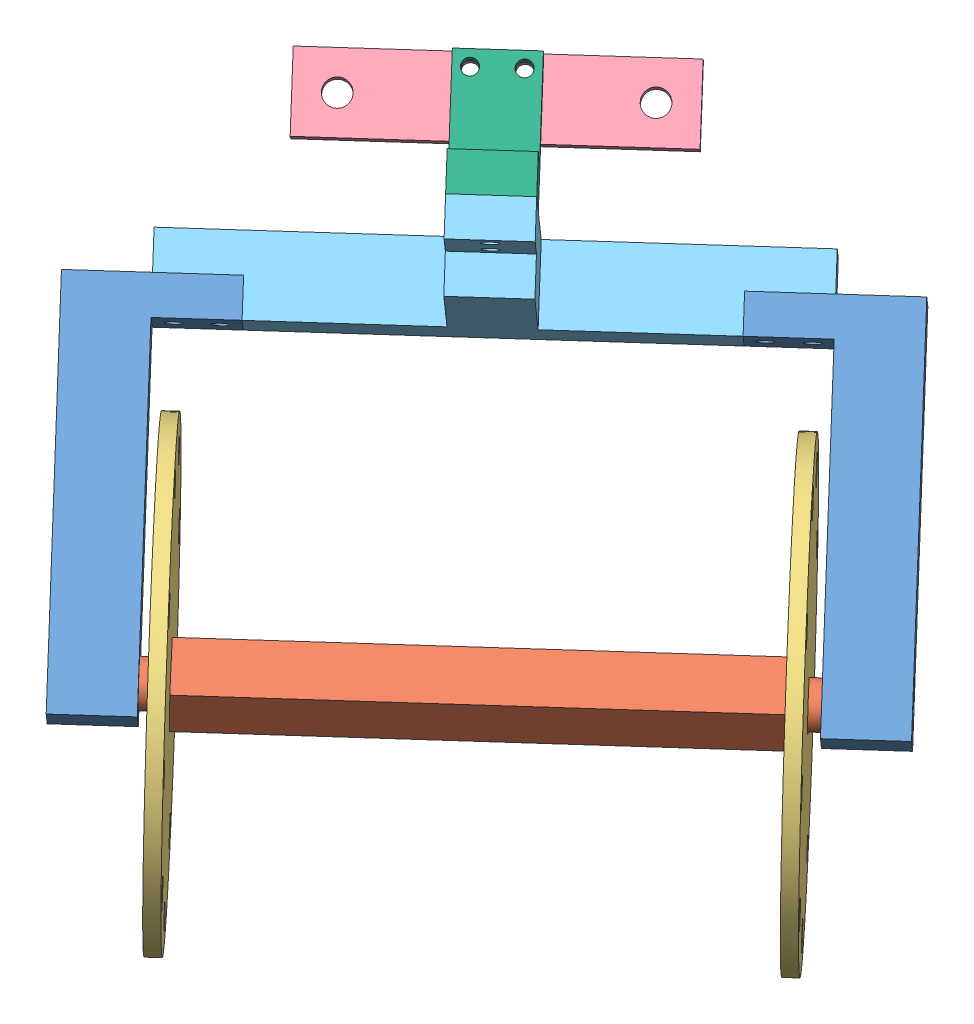
SolidWorks assembly assembly_20241201, configuration 默认. Lengths in mm.
Overall size (218.69 227.91 217.94).
8 component instances, 6 part files, 19 mates.
Components (placement in the parent):
- connecter_ear_3D_printing_20241201-3: connecter_ear_3D_printing_20241201 [默认] at (273.7366 -111.631 197.0743) x (-0.457434 0.731579 -0.505516) z (0.507347 0.681586 0.527294) size (98.5 40 16)
- connecter_ear_3D_printing_20241201-4: connecter_ear_3D_printing_20241201 [默认] at (383.2831 -113.9215 94.6325) x (-0.457434 0.731579 -0.505516) z (-0.507347 -0.681586 -0.527294) size (98.5 40 16)
- core_stick_3D_printing_20241201-3: core_stick_3D_printing_20241201 [默认] at (378.1709 -113.8146 99.4132) x (0.272303 0.923395 0.270542) z (0.626497 -0.383547 0.678523) size (15 176 15)
- sidewall_acrylic_4mm_20241201-5: sidewall_acrylic_4mm_20241201 [默认] at (378.1709 -113.8146 99.4132) x (0.65086 -0.288029 0.702439) z (0.207434 0.9575 0.200412) size (120 4 120)
- sidewall_acrylic_4mm_20241201-6: sidewall_acrylic_4mm_20241201 [默认] at (275.9275 -111.6768 195.0255) x (0.65086 -0.288029 0.702439) z (0.207434 0.9575 0.200412) size (120 4 120)
- connecter_tail_acrylic_4mm_20241202-1: connecter_tail_acrylic_4mm_20241202 [默认] at (296.1906 12.0688 108.5013) x (0.73031 -0.01527 -0.682945) z (0.457434 -0.731579 0.505516) size (90 4 20)
- connecter_body_3D_printing_20241201-5: connecter_body_3D_printing_20241201 [默认] at (282.7664 -39.6184 95.3018) x (-0.73031 0.01527 0.682945) z (0.507347 0.681586 0.527294) size (150 20 86)
- connecter_fixer_3D_printing-1: connecter_fixer_3D_printing [默认] at (317.266 6.7295 131.1578) x (0.73031 -0.01527 -0.682945) z (-0.457434 0.731579 -0.505516) size (20 25 35)
Mates (geometry in assembly coordinates):
- 同心6: concentric anti-aligned: cylinder of connecter_ear_3D_printing_20241201-3 through (259.1304 -111.3256 210.7332) axis (0.73031 -0.01527 -0.682945) radius 6.5; cylinder of core_stick_3D_printing_20241201-3 through (392.7771 -114.12 85.7543) axis (-0.73031 0.01527 0.682945) radius 6
- 同心7: concentric aligned: cylinder of core_stick_3D_printing_20241201-3 through (392.7771 -114.12 85.7543) axis (-0.73031 0.01527 0.682945) radius 6; cylinder of sidewall_acrylic_4mm_20241201-5 through (381.0922 -113.8757 96.6814) axis (-0.73031 0.01527 0.682945) radius 6.6
- 同心9: concentric anti-aligned: cylinder of core_stick_3D_printing_20241201-3 through (264.2426 -111.4325 205.9526) axis (0.73031 -0.01527 -0.682945) radius 6; cylinder of sidewall_acrylic_4mm_20241201-6 through (278.8488 -111.7379 192.2937) axis (-0.73031 0.01527 0.682945) radius 6.6
- 重合6: coincident anti-aligned: plane of core_stick_3D_printing_20241201-3 through (278.8488 -111.7379 192.2937) normal (-0.73031 0.01527 0.682945); plane of sidewall_acrylic_4mm_20241201-6 through (278.8488 -111.7379 192.2937) normal (0.73031 -0.01527 -0.682945)
- 同心17: concentric aligned: cylinder of connecter_ear_3D_printing_20241201-4 through (397.8893 -114.2269 80.9736) axis (-0.73031 0.01527 0.682945) radius 6.5; cylinder of core_stick_3D_printing_20241201-3 through (392.7771 -114.12 85.7543) axis (-0.73031 0.01527 0.682945) radius 6
- 重合14: coincident anti-aligned: plane of core_stick_3D_printing_20241201-3 through (378.1709 -113.8146 99.4132) normal (0.73031 -0.01527 -0.682945); plane of sidewall_acrylic_4mm_20241201-5 through (378.1709 -113.8146 99.4132) normal (-0.73031 0.01527 0.682945)
- 同心18: concentric aligned: cylinder of connecter_ear_3D_printing_20241201-4 through (338.6085 -48.0061 52.4142) axis (0.457434 -0.731579 0.505516) radius 2.1; cylinder of connecter_body_3D_printing_20241201-5 through (334.0342 -40.6903 47.3591) axis (0.457434 -0.731579 0.505516) radius 2.1
- 同心19: concentric aligned: cylinder of connecter_ear_3D_printing_20241201-4 through (331.0133 -47.8473 59.5169) axis (0.457434 -0.731579 0.505516) radius 2.1; cylinder of connecter_body_3D_printing_20241201-5 through (326.439 -40.5315 54.4617) axis (0.457434 -0.731579 0.505516) radius 2.1
- 同心20: concentric aligned: cylinder of connecter_ear_3D_printing_20241201-3 through (243.6682 -46.0211 141.1971) axis (0.457434 -0.731579 0.505516) radius 2.1; cylinder of connecter_body_3D_printing_20241201-5 through (239.0939 -38.7053 136.142) axis (0.457434 -0.731579 0.505516) radius 2.1
- 同心21: concentric aligned: circle of connecter_ear_3D_printing_20241201-3; circle of connecter_body_3D_printing_20241201-5
- 重合16: coincident anti-aligned: plane of connecter_ear_3D_printing_20241201-4 through (342.114 -48.0794 49.1361) normal (-0.457434 0.731579 -0.505516); plane of connecter_body_3D_printing_20241201-5 through (287.3408 -46.9342 100.357) normal (0.457434 -0.731579 0.505516)
- 距离1: distance = 3 mm anti-aligned: plane of sidewall_acrylic_4mm_20241201-5 through (381.0922 -113.8757 96.6814) normal (0.73031 -0.01527 -0.682945); plane of connecter_ear_3D_printing_20241201-4 through (383.2831 -113.9215 94.6325) normal (-0.73031 0.01527 0.682945)
- 同心23: concentric aligned: cylinder of connecter_body_3D_printing_20241201-5 through (319.9042 10.2737 133.8998) axis (0.457434 -0.731579 0.505516) radius 2.1; cylinder of connecter_fixer_3D_printing-1 through (315.3299 17.5895 128.8446) axis (0.457434 -0.731579 0.505516) radius 2.1
- 同心24: concentric aligned: cylinder of connecter_body_3D_printing_20241201-5 through (314.6278 3.1852 128.4159) axis (0.457434 -0.731579 0.505516) radius 2.1; cylinder of connecter_fixer_3D_printing-1 through (310.0535 10.501 123.3607) axis (0.457434 -0.731579 0.505516) radius 2.1
- 重合17: coincident anti-aligned: plane of connecter_body_3D_printing_20241201-5 through (282.7664 -39.6184 95.3018) normal (-0.457434 0.731579 -0.505516); plane of connecter_fixer_3D_printing-1 through (317.266 6.7295 131.1578) normal (0.457434 -0.731579 0.505516)
- 平行1: parallel anti-aligned: plane of connecter_tail_acrylic_4mm_20241202-1 through (255.7119 -42.3115 66.4312) normal (0.507347 0.681586 0.527294); plane of connecter_fixer_3D_printing-1 through (309.6558 -3.4943 123.2484) normal (-0.507347 -0.681586 -0.527294)
- 同心25: concentric aligned: cylinder of connecter_tail_acrylic_4mm_20241202-1 through (286.02 12.4604 106.4022) axis (0.507347 0.681586 0.527294) radius 2.1; cylinder of connecter_fixer_3D_printing-1 through (280.9466 5.6445 101.1292) axis (0.507347 0.681586 0.527294) radius 2.1
- 同心26: concentric aligned: cylinder of connecter_tail_acrylic_4mm_20241202-1 through (294.7838 12.2771 98.2068) axis (0.507347 0.681586 0.527294) radius 2.1; cylinder of connecter_fixer_3D_printing-1 through (289.7103 5.4613 92.9339) axis (0.507347 0.681586 0.527294) radius 2.1
- 重合19: coincident anti-aligned: plane of connecter_tail_acrylic_4mm_20241202-1 through (298.22 14.7951 110.6105) normal (0.507347 0.681586 0.527294); plane of connecter_fixer_3D_printing-1 through (309.6558 -3.4943 123.2484) normal (-0.507347 -0.681586 -0.527294)
